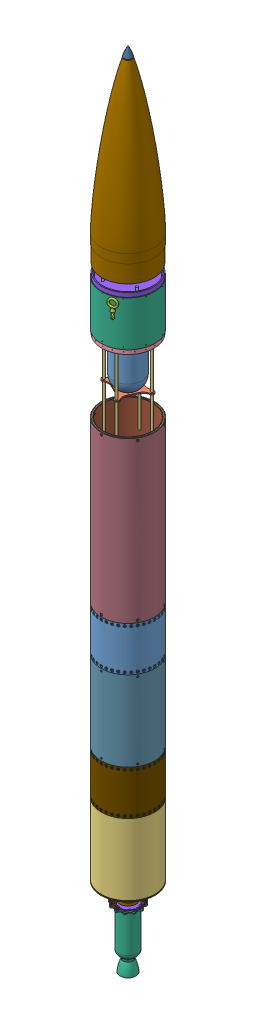
SolidWorks assembly 000042-R01_LAUNCHY-MCLAUNCHFACE_ASSM, configuration Default. Lengths in mm.
Overall size (600.23 4581.73 600.25).
73 component instances, 36 part files, 15 mates.
Components (placement in the parent):
- InertGasTankAssembly-1: InertGasTankAssembly [Default] at (-45.0859 3780.6719 766.6752) x (-0.065477 0 0.997854) z (0.997854 0 0.065477) size (230.67 749.2 230.67)
  - InertGasTank-1: InertGasTank [Default] at (103.6942 61.4344 388.6435) size (165.1 495.3 165.1)
  - InertTankMount-1: InertTankMount [Default] at (103.6942 74.231 388.6435) x (0.935607 0 -0.353044) z (0.353044 0 0.935607) size (177.8 6.35 177.8)
  - InertTankMount-2: InertTankMount [Default] at (103.6942 524.8877 388.6435) x (0.930119 0 -0.367259) z (0.367259 0 0.930119) size (177.8 6.35 177.8)
  - IntertankThreadedRod-PLACEHOLDER-1: IntertankThreadedRod-PLACEHOLDER [Default] at (202.5543 201.0377 431.5334) size (12.7 609.6 12.7)
  - IntertankThreadedRod-PLACEHOLDER-2: IntertankThreadedRod-PLACEHOLDER [Default] at (146.5841 201.0377 289.7833) size (12.7 609.6 12.7)
  - IntertankThreadedRod-PLACEHOLDER-3: IntertankThreadedRod-PLACEHOLDER [Default] at (4.834 201.0377 345.7535) size (12.7 609.6 12.7)
  - IntertankThreadedRod-PLACEHOLDER-4: IntertankThreadedRod-PLACEHOLDER [Default] at (60.8042 201.0377 487.5036) size (12.7 609.6 12.7)
- AviBayAssembly-1: AviBayAssembly [Default] at (561.4896 3378.433 1011.5831) x (-0.941476 0 0.33708) z (-0.33708 0 -0.941476) size (384.07 304.8 384.07)
  - AVI-lower-Bulkhead-1: AVI-lower-Bulkhead [Default] at (173.2577 134.5262 185.231) size (298.45 50.8 298.45)
  - threadedRod-PLACEHOLDER-1: threadedRod-PLACEHOLDER [Default] at (249.4577 131.3512 109.031) size (12.7 304.8 12.7)
  - threadedRod-PLACEHOLDER-2: threadedRod-PLACEHOLDER [Default] at (249.4577 131.3512 261.431) size (12.7 304.8 12.7)
  - threadedRod-PLACEHOLDER-4: threadedRod-PLACEHOLDER [Default] at (97.0577 131.3512 261.431) size (12.7 304.8 12.7)
  - threadedRod-PLACEHOLDER-5: threadedRod-PLACEHOLDER [Default] at (97.0577 131.3512 109.031) size (12.7 304.8 12.7)
  - AviSkin-1: AviSkin [Default] at (173.2577 159.9262 185.231) x (0.309017 0 0.951057) z (-0.951057 0 0.309017) size (304.8 257.18 304.8)
- RecoveryBay Assembly-1: RecoveryBay Assembly [Default] at (459.1192 3848.3058 926.4892) x (-0.941476 0 0.33708) z (-0.33708 0 -0.941476) size (298.45 107.11 414.59)
  - 3014T491_STL EYEBOLT W SHLDR - FOR LIFTING-1: 3014T491_STL EYEBOLT W SHLDR - FOR LIFTING [3014T491] at (53.7722 -7.5278 -182.8441) size (52.39 107.11 23.81)
  - Bulkhead-1: Bulkhead [Default] at (105.5619 -59.1216 70.6102) size (298.45 50.8 298.45)
- NoseCone-1: NoseCone [Default] at (-1094.6773 3878.36 1038.083) x (0.633193 0.008727 -0.773945) z (0.773974 0 0.633217) size (313.65 1073.69 304.8)
  - NoseCone-1: NoseCone [Default] at (1025.2987 1041.6077 1017.0299) x (-0.008727 -0.999962 0) z (0 0 1) size (1016 304.8 304.8)
  - NoseConeTip-2: NoseConeTip [Default] at (1025.3438 1046.7761 1017.0299) x (0.000404 -1 0.000472) z (-0.051616 0.00045 0.998667) size (51.36 45.99 45.99)
- 000043-R01_INERT_GAS_AIRFRAME_ASSM-1: 000043-R01_INERT_GAS_AIRFRAME_ASSM [Default] at (-397.6842 3385.4485 153.9129) x (-0.866025 0 0.5) z (0.5 0 0.866025) size (304.8 914.4 304.8)
  - 000045-R01_INERT_GAS_AF_ID-1: 000045-R01_INERT_GAS_AF_ID [Default] at (-264.4913 286.7106 1009.1239) size (285.75 914.4 285.75)
  - 000046-R01_INERT_GAS_AF_SANDWICH-2: 000046-R01_INERT_GAS_AF_SANDWICH [Default] at (-264.4913 286.7106 1009.1239) size (298.45 914.4 298.45)
  - 000044-R01_INERT_GAS_AF_OD-1: 000044-R01_INERT_GAS_AF_OD [Default] at (-264.4913 286.7106 1009.1239) size (304.8 914.4 304.8)
- 000048-R01_INTERTANK_AF_ASSM-1: 000048-R01_INTERTANK_AF_ASSM [Default] at (-296.4316 1186.1501 1253.8443) x (0.866025 0 -0.5) z (0.5 0 0.866025) size (304.8 457.2 304.8)
  - 000049-R01_INTERTANK_AF_OD-1: 000049-R01_INTERTANK_AF_OD [Default] at (726.7696 286.9878 5.929) size (304.8 457.2 304.8)
  - 000050-R01_INTERTANK_AF_ID-1: 000050-R01_INTERTANK_AF_ID [Default] at (726.7696 286.9878 5.929) size (285.75 457.2 285.75)
  - 000051-R01_INTERTANK_AF_SANDWICH-1: 000051-R01_INTERTANK_AF_SANDWICH [Default] at (726.7696 286.9878 5.929) size (298.45 457.2 298.45)
- 000053-R01_LOX_TANK_ASSM-1: 000053-R01_LOX_TANK_ASSM [Default] at (212.1292 1311.5334 638.6599) size (399.02 341.25 399.02)
  - 000052-R01_TANK_BULKHEAD-1: 000052-R01_TANK_BULKHEAD [Default] at (123.8047 117.1544 256.9343) size (292.1 88.08 292.1)
  - 000055-R01_LOX_TANK_WALL-1: 000055-R01_LOX_TANK_WALL [Default] at (123.8047 -92.3956 256.9343) size (304.8 254 304.8)
  - 000052-R01_TANK_BULKHEAD-2: 000052-R01_TANK_BULKHEAD [Default] at (123.8047 -47.9456 256.9343) x (-0.866025 0 -0.5) z (-0.5 0 0.866025) size (292.1 88.08 292.1)
- 000054-R01_LNG_TANK_ASSM-1: 000054-R01_LNG_TANK_ASSM [Default] at (509.5759 1900.113 640.8954) x (0.866025 0 0.5) z (-0.5 0 0.866025) size (399.02 341.25 399.02)
  - 000056-R01_LNG_TANK_WALL-1: 000056-R01_LNG_TANK_WALL [Default] at (-23.029 30.2249 307.3966) size (304.8 254 304.8)
  - 000052-R01_TANK_BULKHEAD-1: 000052-R01_TANK_BULKHEAD [Default] at (-23.029 239.7749 307.3966) size (292.1 88.08 292.1)
  - 000052-R01_TANK_BULKHEAD-2: 000052-R01_TANK_BULKHEAD [Default] at (-23.029 74.6749 307.3966) x (0.5 0 -0.866025) z (-0.866025 0 -0.5) size (292.1 88.08 292.1)
- 000067-R01_ENGINE_ASSM-2: 000067-R01_ENGINE_ASSM [Default] at (233.6076 609.2457 758.5124) size (600.23 865.07 600.23)
  - 000057-R01_FIN_CAN_TUBE_ASSM-1: 000057-R01_FIN_CAN_TUBE_ASSM [Default] at (22.4149 3.3111 -251.7381) x (0.98247 0 -0.186422) z (0.186422 0 0.98247) size (304.8 406.4 304.8)
    - 000058-R01_FIN_CAN_TUBE_ID-1: 000058-R01_FIN_CAN_TUBE_ID [Default] at (6.0261 200.1811 396.9011) size (285.75 406.4 285.75)
    - 000059-R01_FIN_CAN_TUBE_OD-1: 000059-R01_FIN_CAN_TUBE_OD [Default] at (6.0261 200.1811 396.9011) size (304.8 406.4 304.8)
    - 000060-R01_FIN_CAN_TUBE_SANDWICH-1: 000060-R01_FIN_CAN_TUBE_SANDWICH [Default] at (6.0261 200.1811 396.9011) size (298.45 406.4 298.45)
  - 000014-R02_REMOVE_BEFORE_FLIGHT_ASSM-1: 000014-R02_REMOVE_BEFORE_FLIGHT_ASSM [Default] at (95.1285 -172.8675 142.1107) x (-0.819749 0 0.572723) z (-0.572723 0 -0.819749) size (431.05 503.94 431.05)
    - 000030-R02_FILM_COOLING_VOLUTE-2: 000030-R02_FILM_COOLING_VOLUTE [Default] at (-8.7806 254.8412 0) x (-0.965926 0 -0.258819) z (0.258819 0 -0.965926) size (156.79 34.88 257.08)
    - 000001-R05_RBF_TCA-2: 000001-R05_RBF_TCA [Default] at (-8.7806 -14.701 0) x (0 -1 0) z (0 0 1) size (343.5 185.64 158.75)
    - 000015-R05_PINTLE_INJECT_ASSM-1: 000015-R05_PINTLE_INJECT_ASSM [Default] at (86.4435 164.1172 71.5928) x (-0.866025 0 0.5) z (-0.5 0 -0.866025) size (158.75 36.86 158.75)
      - 000033-R01_PINTLE_BOTTOM_PLATE-1: 000033-R01_PINTLE_BOTTOM_PLATE [Default] at (46.67 88.1839 109.6132) size (87.7 15.24 87.7)
      - 000032-R02_PINTLE_MIDDLE_PLATE-1: 000032-R02_PINTLE_MIDDLE_PLATE [Default] at (46.67 92.7382 109.6132) size (158.75 29.57 158.75)
      - 000031-R01_PINTLE_UPPER_PLATE-1: 000031-R01_PINTLE_UPPER_PLATE [Default] at (46.67 125.0393 109.6132) size (90.17 15.27 90.17)
      - MISUMI_MSBH6-20-1: MISUMI_MSBH6-20 [Default] at (8.57 121.0393 109.6132) x (0 -1 0) z (0 0 1) size (31 9 9)
    - engine-side-clevis-1: engine-side-clevis [Default] at (-8.7806 273.8912 0) x (0.707107 0 -0.707107) z (0.707107 0 0.707107) size (19.27 25.77 57.15)
    - 000012_R04_ASI_ASSEM-1: 000012_R04_ASI_ASSEM [Default] at (-8.7806 251.1654 0) x (-0.959573 0 0.281459) z (-0.281459 0 -0.959573) size (117.68 93.77 117.68)
      - 000011-R02_ASI_TOP-1: 000011-R02_ASI_TOP [Default] at (0 37.9912 0) x (-0.924896 0 -0.380219) z (0.380219 0 -0.924896) size (90.17 60.14 90.17)
      - 000011-R02_ASI_BOTTOM-1: 000011-R02_ASI_BOTTOM [Default] at (0 4.4632 0) x (0.915191 0 -0.40302) z (0.40302 0 0.915191) size (30.48 24.13 30.48)
      - 000010-R02_ASI-1: 000010-R02_ASI [Default] at (0 63.3912 0) x (-0.133168 0 -0.991093) z (0.991093 0 -0.133168) size (45.72 18.88 45.72)
    - 000061-R01_THRUST_MOUNT_ASSM-6: 000061-R01_THRUST_MOUNT_ASSM [Default] at (111.4343 329.5064 -151.8672) x (-0.196474 0.979436 -0.045863) z (0.562368 0.15088 0.813005) size (122.1 89.38 60.95) (flexible)
      - 000029-R01_LAUNCH_MOUNT_CLEVIS-1: 000029-R01_LAUNCH_MOUNT_CLEVIS [Default] at (62.1337 58.6887 43.4668) x (0.979436 -0.133943 0.15088) z (-0.171358 -0.157515 0.972536) size (31.75 38.1 50.8)
      - THREADED_ROD-1: THREADED_ROD [Default] at (45.0805 88.7224 45.3265) x (0.280946 0.444914 -0.850365) z (0.288612 0.805871 0.516987) size (12.7 50.8 12.7)
      - 8405K111_THRUST-RATED BALL JOINT ROD END-1: 8405K111_THRUST-RATED BALL JOINT ROD END [8405K111] at (-12.2705 113.2011 39.186) x (0.364505 0.906954 0.211118) z (-0.171358 -0.157515 0.972536) size (19.88 46.6 9.53)
      - 8405K111_THRUST-RATED BALL JOINT ROD END-2: 8405K111_THRUST-RATED BALL JOINT ROD END [8405K111] at (49.9702 86.6353 45.85) x (-0.364505 -0.906954 -0.211118) z (-0.171358 -0.157515 0.972536) size (19.88 46.6 9.53)
    - engine-side-clevis-6: engine-side-clevis [Default] at (-8.7806 273.8912 0) x (0.258819 0 0.965926) z (-0.965926 0 0.258819) size (19.27 25.77 57.15)
    - engine-side-clevis-7: engine-side-clevis [Default] at (-8.7806 273.8912 0) x (-0.965926 0 -0.258819) z (0.258819 0 -0.965926) size (19.27 25.77 57.15)
    - 000061-R01_THRUST_MOUNT_ASSM-7: 000061-R01_THRUST_MOUNT_ASSM [Default] at (62.6329 329.5064 180.0427) x (0.137955 0.979436 -0.14722) z (-0.985267 0.15088 0.080522) size (122.1 89.38 60.95) (flexible)
      - 000029-R01_LAUNCH_MOUNT_CLEVIS-1: 000029-R01_LAUNCH_MOUNT_CLEVIS [Default] at (62.1337 58.6887 43.4668) x (0.979436 -0.133943 0.15088) z (-0.171358 -0.157515 0.972536) size (31.75 38.1 50.8)
      - THREADED_ROD-1: THREADED_ROD [Default] at (38.0046 91.7425 44.5689) x (-0.001409 0.240201 0.970722) z (-0.402772 -0.888639 0.219305) size (12.7 50.8 12.7)
      - 8405K111_THRUST-RATED BALL JOINT ROD END-1: 8405K111_THRUST-RATED BALL JOINT ROD END [8405K111] at (-12.2705 113.2011 39.186) x (0.364505 0.906954 0.211118) z (-0.171358 -0.157515 0.972536) size (19.88 46.6 9.53)
      - 8405K111_THRUST-RATED BALL JOINT ROD END-2: 8405K111_THRUST-RATED BALL JOINT ROD END [8405K111] at (49.9702 86.6353 45.85) x (-0.364505 -0.906954 -0.211118) z (-0.171358 -0.157515 0.972536) size (19.88 46.6 9.53)
    - 000061-R01_THRUST_MOUNT_ASSM-8: 000061-R01_THRUST_MOUNT_ASSM [Default] at (-200.4089 329.5064 -28.1755) x (0.058519 0.979436 0.193083) z (0.4229 0.15088 -0.893527) size (128.32 90.23 60.95) (flexible)
      - 000029-R01_LAUNCH_MOUNT_CLEVIS-1: 000029-R01_LAUNCH_MOUNT_CLEVIS [Default] at (62.1337 58.6887 43.4668) x (-0.979436 0.133943 -0.15088) z (0.171358 0.157515 -0.972536) size (31.75 38.1 50.8)
      - THREADED_ROD-1: THREADED_ROD [Default] at (38.0048 91.7424 44.5689) x (0.186107 0.194437 -0.963098) z (0.3572 0.899761 0.250674) size (12.7 50.8 12.7)
      - 8405K111_THRUST-RATED BALL JOINT ROD END-1: 8405K111_THRUST-RATED BALL JOINT ROD END [8405K111] at (-12.2705 113.2011 39.186) x (0.364505 0.906954 0.211118) z (-0.171358 -0.157515 0.972536) size (19.88 46.6 9.53)
      - 8405K111_THRUST-RATED BALL JOINT ROD END-2: 8405K111_THRUST-RATED BALL JOINT ROD END [8405K111] at (49.9702 86.6353 45.85) x (0.364505 0.906954 0.211118) z (0.171358 0.157515 -0.972536) size (19.88 46.6 9.53)
    - 000066-R01_THRUST_MOUNT-1: 000066-R01_THRUST_MOUNT [Default] at (-8.7806 370.0097 0) x (0.707107 0 -0.707107) z (0.707107 0 0.707107) size (304.8 38.1 304.8)
Mates (geometry in assembly coordinates):
- Concentric36: concentric aligned: circle of InertGasTankAssembly-1/InertGasTank-1; cylinder of AviBayAssembly-1/AVI-lower-Bulkhead-1 through (335.9339 3561.753 895.5942) axis (0 1 0) radius 92.075
- Concentric37: concentric aligned: cylinder of InertGasTankAssembly-1/IntertankThreadedRod-PLACEHOLDER-4 through (437.3903 2970.0342 859.2694) axis (0 1 0) radius 6.35; cylinder of AviBayAssembly-1/AVI-lower-Bulkhead-1 through (437.3903 3541.5342 859.2694) axis (0 1 0) radius 5.7544
- Distance9: distance = 38.1 mm aligned: plane of InertGasTankAssembly-1/IntertankThreadedRod-PLACEHOLDER-4 through (437.3903 3579.6342 859.2694) normal (0 1 0); plane of AviBayAssembly-1/AVI-lower-Bulkhead-1 through (201.4205 3541.5342 943.7546) normal (0 1 0)
- Concentric42: concentric anti-aligned: cylinder of AviBayAssembly-1/AVI-lower-Bulkhead-1 through (335.9339 3561.753 895.5942) axis (0 1 0) radius 149.225; cylinder of RecoveryBay Assembly-1/Bulkhead-1 through (335.9339 3789.1842 895.5942) axis (0 -1 0) radius 149.225
- Distance10: distance = 25.4 mm anti-aligned: plane of AviBayAssembly-1/threadedRod-PLACEHOLDER-1 through (289.879 3814.5842 993.0202) normal (0 1 0); plane of RecoveryBay Assembly-1/Bulkhead-1 through (201.4205 3789.1842 943.7546) normal (0 -1 0)
- Coincident18: coincident anti-aligned: plane of 000048-R01_INTERTANK_AF_ASSM-1/000049-R01_INTERTANK_AF_OD-1 through (335.9339 1473.1379 895.5942) normal (0 -1 0); plane of 000053-R01_LOX_TANK_ASSM-1/000055-R01_LOX_TANK_WALL-1 through (335.9339 1473.1379 895.5942) normal (0 1 0)
- Concentric48: concentric aligned: cylinder of 000048-R01_INTERTANK_AF_ASSM-1/000049-R01_INTERTANK_AF_OD-1 through (335.9339 1930.3379 895.5942) axis (0 -1 0) radius 152.4; cylinder of 000053-R01_LOX_TANK_ASSM-1/000055-R01_LOX_TANK_WALL-1 through (335.9339 1473.1379 895.5942) axis (0 -1 0) radius 152.4
- Concentric49: concentric aligned: cylinder of 000048-R01_INTERTANK_AF_ASSM-1/000049-R01_INTERTANK_AF_OD-1 through (335.9339 1930.3379 895.5942) axis (0 -1 0) radius 152.4; cylinder of 000054-R01_LNG_TANK_ASSM-1/000056-R01_LNG_TANK_WALL-1 through (335.9339 2184.3379 895.5942) axis (0 -1 0) radius 152.4
- Concentric50: concentric aligned: cylinder of 000048-R01_INTERTANK_AF_ASSM-1/000051-R01_INTERTANK_AF_SANDWICH-1 through (465.1666 1917.6379 820.9817) axis (0.866025 0 -0.5) radius 6.35; cylinder of 000054-R01_LNG_TANK_ASSM-1/000052-R01_TANK_BULKHEAD-2 through (456.8509 1917.6379 825.7828) axis (0.866025 0 -0.5) radius 3.9688
- Concentric52: concentric anti-aligned: cylinder of 000043-R01_INERT_GAS_AIRFRAME_ASSM-1/000044-R01_INERT_GAS_AF_OD-1 through (335.9339 2184.3379 895.5942) axis (0 1 0) radius 152.4; cylinder of 000054-R01_LNG_TANK_ASSM-1/000056-R01_LNG_TANK_WALL-1 through (335.9339 2184.3379 895.5942) axis (0 -1 0) radius 152.4
- Concentric53: concentric aligned: cylinder of 000043-R01_INERT_GAS_AIRFRAME_ASSM-1/000046-R01_INERT_GAS_AF_SANDWICH-2 through (465.1666 2197.0379 970.2067) axis (0.866025 0 0.5) radius 6.35; cylinder of 000054-R01_LNG_TANK_ASSM-1/000052-R01_TANK_BULKHEAD-1 through (456.8509 2197.0379 965.4057) axis (0.866025 0 0.5) radius 3.9688
- Concentric56: concentric anti-aligned: cylinder of AviBayAssembly-1/AviSkin-1 through (335.9339 3795.5342 895.5942) axis (0 -1 0) radius 152.4; cylinder of 000043-R01_INERT_GAS_AIRFRAME_ASSM-1/000044-R01_INERT_GAS_AF_OD-1 through (335.9339 2184.3379 895.5942) axis (0 1 0) radius 152.4
- Concentric57: concentric anti-aligned: cylinder of AviBayAssembly-1/AviSkin-1 through (335.9339 3795.5342 895.5942) axis (0 -1 0) radius 152.4; cylinder of NoseCone-1/NoseCone-1 through (335.9339 4990.52 895.5942) axis (0 1 0) radius 149.225
- Concentric59: concentric aligned: cylinder of 000067-R01_ENGINE_ASSM-2/000057-R01_FIN_CAN_TUBE_ASSM-1/000059-R01_FIN_CAN_TUBE_OD-1 through (335.9339 1219.1379 895.5942) axis (0 -1 0) radius 152.4; cylinder of 000053-R01_LOX_TANK_ASSM-1/000052-R01_TANK_BULKHEAD-2 through (335.9339 1181.8605 895.5942) axis (0 -1 0) radius 139.6229
- Coincident23: coincident anti-aligned: plane of 000053-R01_LOX_TANK_ASSM-1/000052-R01_TANK_BULKHEAD-2 through (215.0169 1219.1379 825.7828) normal (0 -1 0); plane of 000067-R01_ENGINE_ASSM-2/000057-R01_FIN_CAN_TUBE_ASSM-1/000060-R01_FIN_CAN_TUBE_SANDWICH-1 through (335.9339 1219.1379 895.5942) normal (0 1 0)
